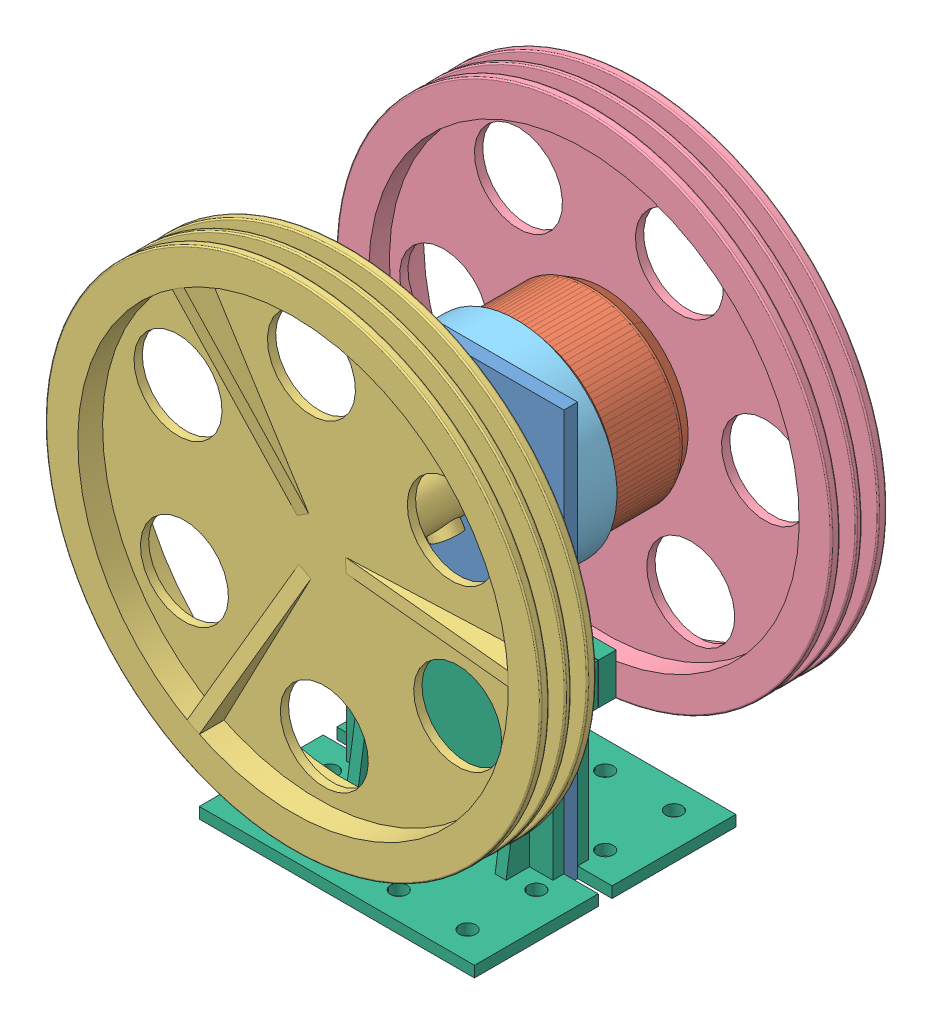
SolidWorks assembly 轮装配体, configuration 默认. Lengths in mm.
Overall size (248.36 248.36 125.7).
7 component instances, 6 part files, 19 mates.
Components (placement in the parent):
- 加厚加粗碳纤维竖板-6: 加厚加粗碳纤维竖板 [默认] at (-273.5387 0 0) x (-1 0 0) z (0 -1 0) size (75 5 150)
- RoboMaster GM6020 直流无刷电机.step-1: RoboMaster GM6020 直流无刷电机.step [默认] at (-311.0387 113 -127.3479) x (0.5 0.866025 0) z (0 0 -1) size (66.7 66.7 45)
- 卷筒2.2实验-1: 卷筒2.2实验 [默认] at (-311.0387 113 6.7) x (0.534871 -0.844933 0) z (0 0 1) size (180 180 60.8)
- 卷筒2实验-1: 卷筒2实验 [默认] at (-311.0387 113 -44.8) x (0.534871 -0.844933 0) z (0.844933 0.534871 0) size (180 113.5 180)
- 加厚加粗电机固定-1: 加厚加粗电机固定 [默认] at (-311.0387 113 -5) x (0.787155 -0.616755 0) z (0.616755 0.787155 0) size (73 20.3 73)
- L型定位板-1: L型定位板 [默认] at (-361.0387 0 -5) size (100 75 47.4)
- L型定位板-2: L型定位板 [默认] at (-261.0387 0 0) x (-1 0 0) z (0 0 -1) size (100 75 47.4)
Mates (geometry in assembly coordinates):
- 重合83: coincident aligned: plane of 加厚加粗碳纤维竖板-6 through (-273.5387 0 0) normal (0 0 1)
- 重合86: coincident anti-aligned: plane of 卷筒2.2实验-1 through (-302.9773 114.8484 12.7) normal (-0.844933 -0.534871 0); plane of 卷筒2实验-1 through (-305.9191 119.4956 -52.4) normal (0.844933 0.534871 0)
- 同心28: concentric aligned: circle of 卷筒2.2实验-1; circle of 卷筒2实验-1
- 同心29: concentric aligned: cylinder of RoboMaster GM6020 直流无刷电机.step-1 through (-311.0387 132.25 -10.8) axis (0 0 1) radius 2.9; cylinder of 加厚加粗电机固定-1 through (-311.0387 132.25 -10.3) axis (0 0 1) radius 4.1
- 同心30: concentric aligned: cylinder of RoboMaster GM6020 直流无刷电机.step-1 through (-311.0387 113 -54.35) axis (0 0 1) radius 9; cylinder of 加厚加粗电机固定-1 through (-311.0387 113 -10.3) axis (0 0 1) radius 11.1
- 重合87: coincident anti-aligned: plane of RoboMaster GM6020 直流无刷电机.step-1 through (-311.0387 113 -10.3) normal (0 0 1); plane of 加厚加粗电机固定-1 through (-311.0387 113 -10.3) normal (0 0 -1)
- 同心31: concentric aligned: cylinder of RoboMaster GM6020 直流无刷电机.step-1 through (-328.7522 122.286 -52.3) axis (0 0 -1) radius 2; cylinder of 卷筒2实验-1 through (-328.7522 122.286 -48.3) axis (0 0 -1) radius 1.9
- 同心32: concentric aligned: cylinder of RoboMaster GM6020 直流无刷电机.step-1 through (-311.0387 113 -54.35) axis (0 0 1) radius 9; cylinder of 卷筒2实验-1 through (-311.0387 113 -52.3) axis (0 0 1) radius 6
- 重合88: coincident anti-aligned: plane of RoboMaster GM6020 直流无刷电机.step-1 through (-311.0387 113 -52.3) normal (0 0 -1); plane of 卷筒2实验-1 through (-311.0387 113 -52.3) normal (0 0 1)
- 同心33: concentric anti-aligned: circle of 卷筒2.2实验-1; circle of 卷筒2实验-1
- 同心34: concentric anti-aligned: cylinder of 加厚加粗碳纤维竖板-6 through (-311.0387 132.25 -5) axis (0 0 1) radius 4.1; cylinder of 加厚加粗电机固定-1 through (-311.0387 132.25 0) axis (0 0 -1) radius 4.1
- 同心35: concentric aligned: cylinder of 加厚加粗碳纤维竖板-6 through (-311.0387 113 -5) axis (0 0 1) radius 11.1; cylinder of 加厚加粗电机固定-1 through (-311.0387 113 -10.3) axis (0 0 1) radius 11.1
- 重合91: coincident anti-aligned: plane of 加厚加粗碳纤维竖板-6 through (-273.5387 0 -5) normal (0 0 -1); plane of 加厚加粗电机固定-1 through (-311.0387 113 -5) normal (0 0 1)
- 重合92: coincident anti-aligned: plane of 加厚加粗碳纤维竖板-6 through (-273.5387 0 -5) normal (0 0 -1); plane of L型定位板-1 through (-361.0387 4 -5) normal (0 0 1)
- 重合93: coincident aligned: plane of 加厚加粗碳纤维竖板-6 through (-273.5387 0 -5) normal (0 -1 0); plane of L型定位板-1 through (-361.0387 0 -5) normal (0 -1 0)
- 重合94: coincident aligned: plane of 加厚加粗碳纤维竖板-6 through (-273.5387 0 -5) normal (1 0 0); plane of L型定位板-1 through (-273.5387 0 -9) normal (1 0 0)
- 重合95: coincident anti-aligned: plane of 加厚加粗碳纤维竖板-6 through (-273.5387 0 0) normal (0 0 1); plane of L型定位板-2 through (-261.0387 4 0) normal (0 0 -1)
- 重合96: coincident aligned: plane of L型定位板-1 through (-361.0387 0 -5) normal (0 -1 0); plane of L型定位板-2 through (-261.0387 0 0) normal (0 -1 0)
- 重合97: coincident aligned: plane of L型定位板-1 through (-348.5387 0 -9) normal (-1 0 0); plane of L型定位板-2 through (-348.5387 0 4) normal (-1 0 0)
